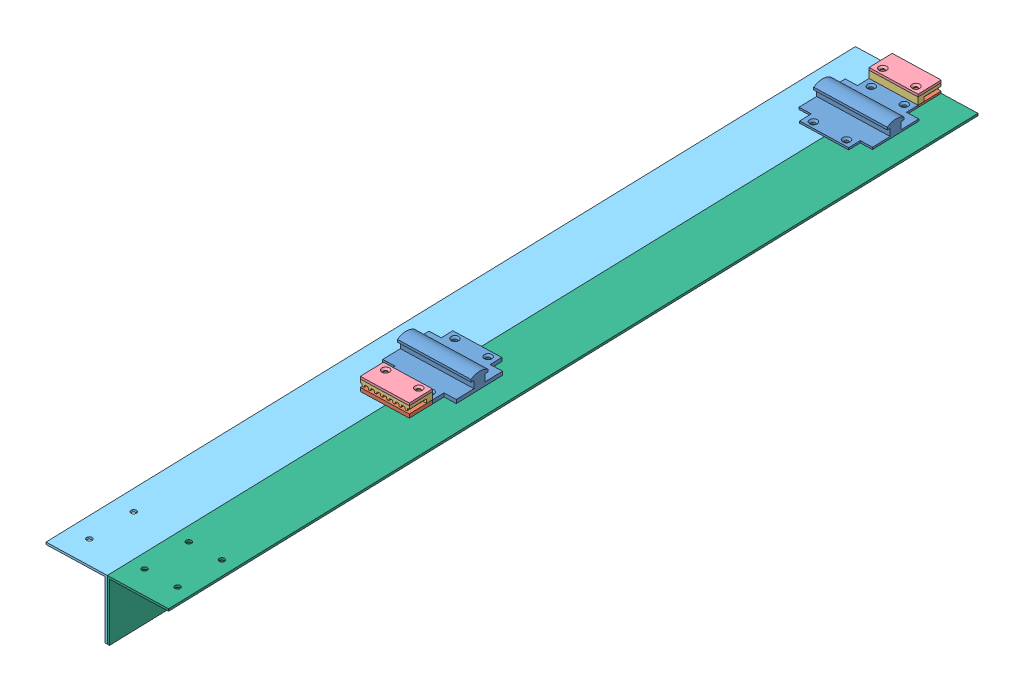
SolidWorks assembly X軸手臂組, configuration 預設. Lengths in mm.
Overall size (120.44 63.7 702.63).
10 component instances, 6 part files, 24 mates.
Components (placement in the parent):
- 鋁擠型用滑塊-1: 鋁擠型用滑塊 [預設] at (-104.2154 -129.3265 -33.7363) x (0.029262 0 0.999572) z (0.999572 0 -0.029262) size (60 13.17 60)
- 鋁擠型用滑塊-2: 鋁擠型用滑塊 [預設] at (-33.7066 -127.4369 324.3538) x (-0.029262 0 -0.999572) z (-0.999572 0 0.029262) size (60 13.17 60)
- 皮帶壓制墊片-3: 皮帶壓制墊片 [預設] at (-62.5233 -124.4369 365.2145) x (-0.999572 0 0.029262) z (0 -1 0) size (40 20 3)
- 皮帶壓制墊片-4: 皮帶壓制墊片 [預設] at (-75.3987 -126.3265 -74.5971) x (0.999572 0 -0.029262) z (0 -1 0) size (40 20 3)
- 皮帶壓制片-1: 皮帶壓制片 [預設] at (-62.5233 -118.4369 365.2145) x (-0.999572 0 0.029262) z (0 -1 0) size (40 20 6)
- 皮帶壓制片-2: 皮帶壓制片 [預設] at (-75.3987 -120.3265 -74.5971) x (0.999572 0 -0.029262) z (0 -1 0) size (40 20 6)
- 皮帶壓制鈑金-3: 皮帶壓制鈑金 [預設] at (-75.3987 -120.3265 -74.5971) x (-0.999572 0 0.029262) z (0 1 0) size (40 20 2)
- 皮帶壓制鈑金-4: 皮帶壓制鈑金 [預設] at (-62.5233 -118.4369 365.2145) x (0.999572 0 -0.029262) z (0 1 0) size (40 20 2)
- 角鋁-下700mm-1: 角鋁-下700mm [預設] at (-55.2077 -127.9623 615.1075) x (0 -1 0) z (-0.029262 0 -0.999572) size (50 50 700)
- 角鋁700mm-1: 角鋁700mm [預設] at (-55.2077 -127.9623 615.1075) x (0.999572 0 -0.029262) z (-0.029262 0 -0.999572) size (50 50 700)
Mates (geometry in assembly coordinates):
- 重合/共線/共點43: coincident anti-aligned: plane of 鋁擠型用滑塊-2 through (-92.8031 -127.4369 356.0967) normal (0.029262 0 0.999572); plane of 皮帶壓制墊片-3 through (-42.8245 -127.4369 354.6336) normal (-0.029262 0 -0.999572)
- 重合/共線/共點46: coincident anti-aligned: plane of 鋁擠型用滑塊-1 through (-43.5024 -129.3265 -65.0199) normal (0 0 -1); plane of 皮帶壓制墊片-4 through (-93.5024 -129.3265 -65.0199) normal (0 0 1)
- 重合/共線/共點48: coincident anti-aligned: plane of 皮帶壓制墊片-3 through (-62.5233 -124.4369 365.2145) normal (0 1 0); plane of 皮帶壓制片-1 through (-62.5233 -124.4369 365.2145) normal (0 -1 0)
- 同軸心19: concentric aligned: cylinder of 皮帶壓制墊片-3 through (-49.1754 -127.4369 359.8216) axis (0 1 0) radius 1.75; cylinder of 皮帶壓制片-1 through (-49.1754 -124.4369 359.8216) axis (0 1 0) radius 1.75
- 同軸心20: concentric aligned: cylinder of 皮帶壓制墊片-3 through (-76.1638 -127.4369 360.6117) axis (0 1 0) radius 1.75; cylinder of 皮帶壓制片-1 through (-76.1638 -124.4369 360.6117) axis (0 1 0) radius 1.75
- 重合/共線/共點49: coincident anti-aligned: plane of 皮帶壓制墊片-4 through (-73.5024 -126.3265 -75.0199) normal (0 1 0); plane of 皮帶壓制片-2 through (-73.5024 -126.3265 -75.0199) normal (0 -1 0)
- 同軸心21: concentric aligned: cylinder of 皮帶壓制墊片-4 through (-60.0024 -129.3265 -70.0199) axis (0 1 0) radius 1.75; cylinder of 皮帶壓制片-2 through (-60.0024 -126.3265 -70.0199) axis (0 1 0) radius 1.75
- 同軸心22: concentric aligned: cylinder of 皮帶壓制墊片-4 through (-87.0024 -129.3265 -70.0199) axis (0 1 0) radius 1.75; cylinder of 皮帶壓制片-2 through (-87.0024 -126.3265 -70.0199) axis (0 1 0) radius 1.75
- 重合/共線/共點50: coincident anti-aligned: plane of 皮帶壓制片-1 through (-62.5233 -118.4369 365.2145) normal (0 1 0); plane of 皮帶壓制鈑金-4 through (-62.5233 -118.4369 365.2145) normal (0 -1 0)
- 重合/共線/共點51: coincident anti-aligned: plane of 皮帶壓制片-2 through (-73.5024 -120.3265 -75.0199) normal (0 1 0); plane of 皮帶壓制鈑金-3 through (-73.5024 -120.3265 -75.0199) normal (0 -1 0)
- 同軸心23: concentric aligned: cylinder of 皮帶壓制片-1 through (-49.1754 -124.4369 359.8216) axis (0 1 0) radius 1.75; cylinder of 皮帶壓制鈑金-4 through (-49.1754 -116.4369 359.8216) axis (0 1 0) radius 1.7
- 同軸心24: concentric aligned: cylinder of 皮帶壓制片-1 through (-76.1638 -124.4369 360.6117) axis (0 1 0) radius 1.75; cylinder of 皮帶壓制鈑金-4 through (-76.1638 -116.4369 360.6117) axis (0 1 0) radius 1.7
- 同軸心25: concentric aligned: cylinder of 皮帶壓制片-2 through (-87.0024 -126.3265 -70.0199) axis (0 1 0) radius 1.75; cylinder of 皮帶壓制鈑金-3 through (-87.0024 -118.3265 -70.0199) axis (0 1 0) radius 1.7
- 同軸心26: concentric aligned: cylinder of 皮帶壓制片-2 through (-60.0024 -126.3265 -70.0199) axis (0 1 0) radius 1.75; cylinder of 皮帶壓制鈑金-3 through (-60.0024 -118.3265 -70.0199) axis (0 1 0) radius 1.7
- 重合/共線/共點356: coincident aligned: line of 角鋁-下700mm-1 through (-75.6913 -127.9623 -84.5928) axis (0.029262 0 0.999572); line of 角鋁700mm-1 through (-75.6913 -127.9623 -84.5928) axis (0.029262 0 0.999572)
- 重合/共線/共點357: coincident anti-aligned: line of 角鋁-下700mm-1 through (-55.2077 -127.9623 615.1075) axis (0 -1 0); line of 角鋁700mm-1 through (-55.2077 -177.9623 615.1075) axis (0 1 0)
- 重合/共線/共點365: coincident aligned: line of 鋁擠型用滑塊-1 through (-53.5024 -129.3265 -65.0199) axis (-1 0 0); line of 皮帶壓制墊片-4 through (-53.5024 -129.3265 -65.0199) axis (-1 0 0)
- 重合/共線/共點366: coincident anti-aligned: line of 鋁擠型用滑塊-1 through (-53.5024 -129.3265 -55.0199) axis (0 0 -1); line of 皮帶壓制墊片-4 through (-53.5024 -129.3265 -85.0199) axis (0 0 1)
- 重合/共線/共點367: coincident aligned: line of 鋁擠型用滑塊-2 through (-82.8074 -127.4369 355.804) axis (0.999572 0 -0.029262); line of 皮帶壓制墊片-3 through (-82.8074 -127.4369 355.804) axis (0.999572 0 -0.029262)
- 重合/共線/共點368: coincident aligned: plane of 鋁擠型用滑塊-2 through (-43.1171 -117.4369 344.6378) normal (0.999572 0 -0.029262); plane of 皮帶壓制墊片-3 through (-42.8245 -127.4369 354.6336) normal (0.999572 0 -0.029262)
- 同軸心27: concentric aligned: circle of 鋁擠型用滑塊-2; circle of 角鋁700mm-1
- 同軸心28: concentric aligned: circle of 鋁擠型用滑塊-2; circle of 角鋁700mm-1
- 同軸心29: concentric aligned: circle of 鋁擠型用滑塊-1; circle of 角鋁700mm-1
- 同軸心30: concentric aligned: circle of 鋁擠型用滑塊-1; circle of 角鋁700mm-1
